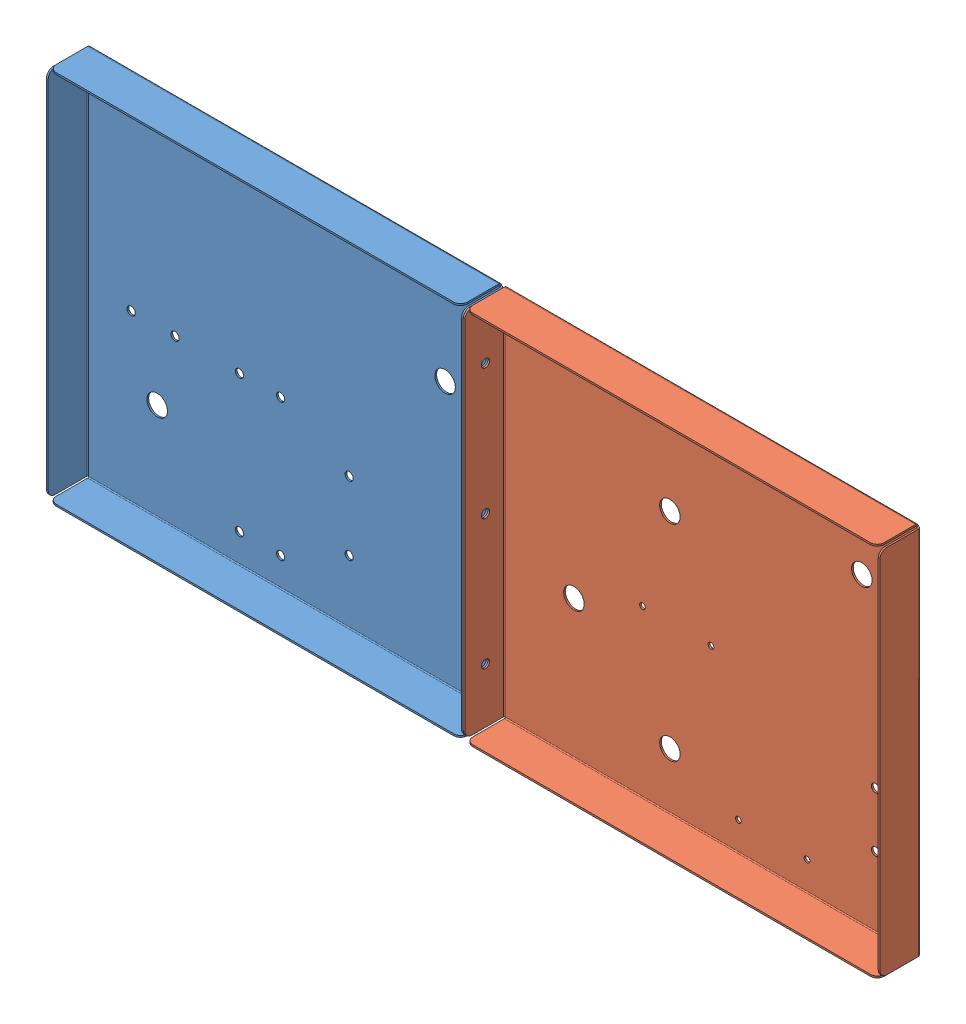
SolidWorks assembly Assem base 222, configuration Default. Lengths in mm.
Overall size (607.95 273.97 30).
2 component instances, 2 part files, 3 mates.
Components (placement in the parent):
- base 2 1-1: base 2 1 [Default] at (33.2292 175.0007 265.8333) size (303.97 273.97 30)
- base 2 2 2-1: base 2 2 2 [Default] at (337.2024 175.0007 265.8333) x (-1 0 0) z (0 0 1) size (303.97 273.97 30)
Mates (geometry in assembly coordinates):
- Coincident1: coincident anti-aligned: plane of base 2 1-1 through (185.2158 175.0007 265.8333) normal (1 0 0); plane of base 2 2 2-1 through (185.2158 175.0007 265.8333) normal (-1 0 0)
- Concentric1: concentric anti-aligned: cylinder of base 2 1-1 through (175.2158 270.0302 279.5833) axis (1 0 0) radius 3; cylinder of base 2 2 2-1 through (195.2158 270.0302 279.5833) axis (-1 0 0) radius 3
- Concentric2: concentric anti-aligned: cylinder of base 2 1-1 through (175.2158 175.0007 279.5833) axis (1 0 0) radius 3; cylinder of base 2 2 2-1 through (195.2158 175.0007 279.5833) axis (-1 0 0) radius 3
